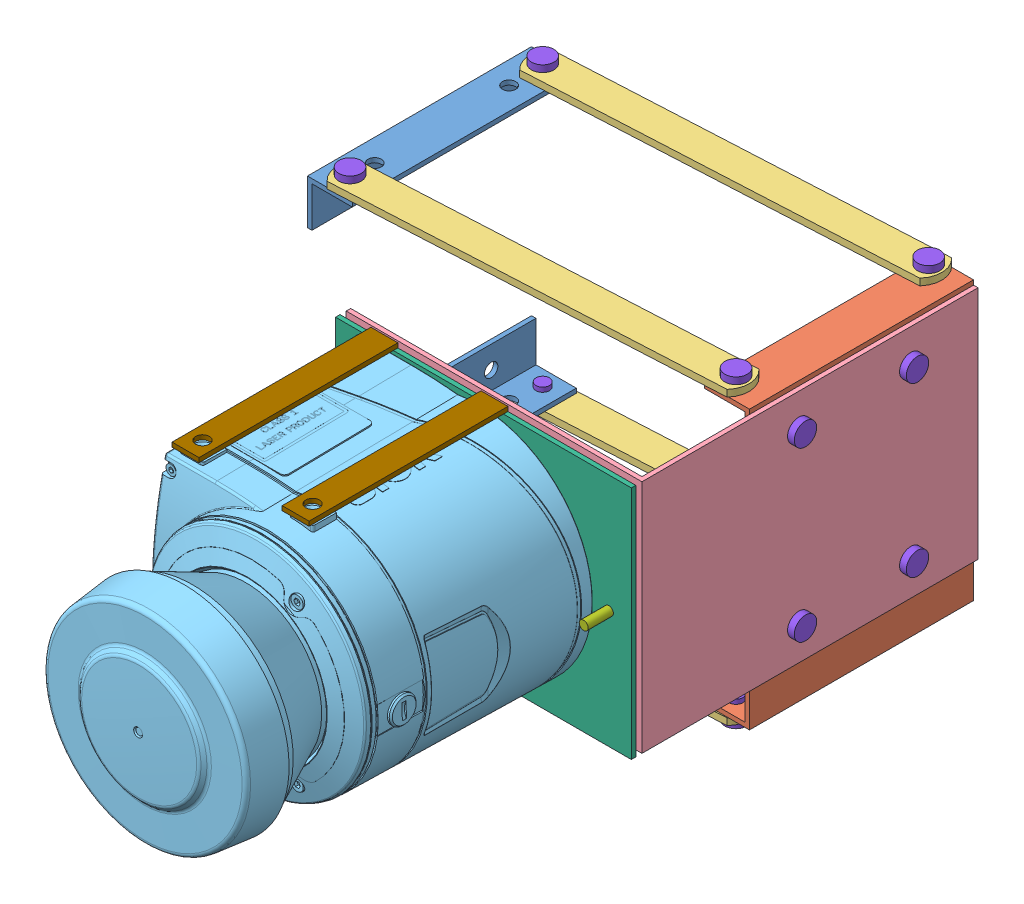
SolidWorks assembly LiDAR Stabilizer, configuration Default. Lengths in mm.
Overall size (193.78 136 307.54).
28 component instances, 9 part files, 52 mates.
Components (placement in the parent):
- l plate-1: l plate [Default] at (18.2462 47.9198 27.6547) size (20 20 100)
- l plate-3: l plate [Default] at (38.2462 -56.0802 27.6547) x (0 1 0) z (0 0 1) size (20 20 100)
- front plate-2: front plate [Default] at (187.0253 67.9198 19.1461) x (0 -1 0) z (0 0 1) size (124 20 100)
- rod-5: rod [Default] at (26.8611 67.9198 27.3205) x (0.998653 0 -0.051882) z (0 1 0) size (176.21 15 3)
- rod-6: rod [Default] at (27.6393 -56.0802 128.3003) x (0.998653 0 -0.051882) z (0 -1 0) size (176.21 15 3)
- rod-7: rod [Default] at (26.8611 67.9198 113.3205) x (0.998653 0 -0.051882) z (0 1 0) size (176.21 15 3)
- rod-8: rod [Default] at (27.6393 -56.0802 42.3003) x (0.998653 0 -0.051882) z (0 -1 0) size (176.21 15 3)
- frontest plate-1: frontest plate [Default] at (207.0253 -39.1421 19.1461) x (0 1 0) z (1 0 0) size (105 150 132)
- LMS111-10100_Dummy-1: LMS111-10100_Dummy [Default] at (80.4216 72.4975 267.6799) x (0.00017 -1 0) z (0 0 1) size (102.32 105.69 161.79)
- lidar base plate-1: lidar base plate [Default] at (2.9052 0 171.893) size (132 105 2)
- angle changing bolt-1: angle changing bolt [Default] at (82.0253 13.3579 164.1461) x (0.352246 -0.935908 0) z (0 0 1) size (10 10 21)
- angle changing bolt-2: angle changing bolt [Default] at (199.0253 13.3579 164.1461) size (10 10 21)
- bolttt-1: bolttt [Default] at (212.0253 50.8579 49.1461) x (0 0 1) z (-1 0 0) size (10 10 10)
- bolttt-2: bolttt [Default] at (212.0253 50.8579 99.1461) x (0 0 1) z (-1 0 0) size (10 10 10)
- bolttt-3: bolttt [Default] at (212.0253 -24.1421 99.1461) x (0 0 1) z (-1 0 0) size (10 10 10)
- bolttt-4: bolttt [Default] at (212.0253 -24.1421 49.1461) x (0 0 1) z (-1 0 0) size (10 10 10)
- bolttt-5: bolttt [Default] at (194.0253 -62.0802 26.1461) x (1 0 0) z (0 1 0) size (10 10 10)
- bolttt-6: bolttt [Default] at (194.0253 -62.0802 112.1461) x (1 0 0) z (0 1 0) size (10 10 10)
- bolttt-7: bolttt [Default] at (30.2462 -62.0802 120.6547) x (1 0 0) z (0 1 0) size (10 10 10)
- bolttt-8: bolttt [Default] at (30.2462 -62.0802 34.6547) x (1 0 0) z (0 1 0) size (10 10 10)
- bolttt-9: bolttt [Default] at (30.2462 73.9198 120.6547) x (1 0 0) z (0 -1 0) size (10 10 10)
- bolttt-10: bolttt [Default] at (30.2462 73.9198 34.6547) x (1 0 0) z (0 -1 0) size (10 10 10)
- bolttt-11: bolttt [Default] at (194.0253 73.9198 26.1461) x (1 0 0) z (0 -1 0) size (10 10 10)
- bolttt-12: bolttt [Default] at (194.0253 73.9198 112.1461) x (1 0 0) z (0 -1 0) size (10 10 10)
- holding lidar-1: holding lidar [Default] at (194.2396 -41.1421 -13.1858) x (1 0 0) z (0 1 0) size (12 88.76 2)
- holding lidar-2: holding lidar [Default] at (242.8499 -41.1421 -13.1858) x (1 0 0) z (0 1 0) size (12 88.76 2)
- holding lidar-3: holding lidar [Default] at (243.0837 65.8579 -13.1858) x (1 0 0) z (0 1 0) size (12 88.76 2)
- holding lidar-4: holding lidar [Default] at (193.9438 65.8579 -13.1858) x (1 0 0) z (0 1 0) size (12 88.76 2)
Mates (geometry in assembly coordinates):
- Coincident8: coincident: plane of assembly; plane of assembly; plane of l plate-1 through (18.2462 47.9198 127.6547) normal (-1 0 0); plane of l plate-3 through (18.2462 -56.0802 127.6547) normal (-1 0 0)
- Coincident9: coincident: plane of assembly; plane of assembly; plane of l plate-1 through (18.2462 47.9198 27.6547) normal (0 0 -1); plane of l plate-3 through (38.2462 -56.0802 27.6547) normal (0 0 -1)
- Coincident10: coincident: plane of assembly; plane of assembly; plane of front plate-2 through (187.0253 67.9198 119.1461) normal (0 1 0); plane of rod-5 through (34.7401 67.9198 34.4213) normal (0 -1 0)
- Coincident11: coincident: circle of assembly; circle of assembly; circle of front plate-2; circle of rod-5
- Coincident12: coincident: circle of assembly; circle of assembly; circle of l plate-1; circle of rod-5
- Coincident13: coincident: circle of assembly; circle of assembly; circle of l plate-1; circle of rod-7
- Coincident14: coincident: circle of front plate-2; circle of rod-7
- Coincident15: coincident: circle of assembly; circle of assembly; circle of front plate-2; circle of rod-8
- Coincident16: coincident: circle of l plate-3; circle of rod-8
- Coincident17: coincident: circle of assembly; circle of assembly; circle of l plate-3; circle of rod-6
- Coincident19: coincident: circle of front plate-2; circle of rod-6
- Parallel1: parallel: plane of assembly; plane of assembly; plane of front plate-2 through (187.0253 67.9198 19.1461) normal (0 0 -1); plane of frontest plate-1 through (209.0253 -39.1421 19.1461) normal (0 0 -1)
- Coincident21: coincident: plane of assembly; plane of assembly; plane of front plate-2 through (207.0253 67.9198 119.1461) normal (1 0 0); plane of frontest plate-1 through (207.0253 -39.1421 19.1461) normal (-1 0 0)
- Coincident22: coincident: line of front plate-2 through (207.0253 -56.0802 19.1461) axis (0 1 0); line of frontest plate-1 through (207.0253 -39.1421 19.1461) axis (0 1 0)
- Lock1: lock: unknown of ?; unknown of ?
- Parallel2: parallel: plane of frontest plate-1 through (209.0253 65.8579 169.1461) normal (0 0 1); plane of lidar base plate-1 through (2.9052 0 171.893) normal (0 0 -1)
- Parallel3: parallel: line of lidar base plate-1 through (209.0253 65.8579 171.893) axis (-1 0 0)
- Parallel4: parallel: line of lidar base plate-1 through (77.0253 65.8579 171.893) axis (0 -1 0)
- Parallel5: parallel: line of lidar base plate-1 through (209.0253 -39.1421 171.893) axis (0 1 0)
- Coincident28: coincident: plane of assembly; plane of assembly; plane of frontest plate-1 through (77.0253 -39.1421 19.1461) normal (-1 0 0); plane of lidar base plate-1 through (77.0253 65.8579 173.893) normal (-1 0 0)
- Coincident30: coincident: plane of assembly; plane of assembly; plane of LMS111-10100_Dummy-1 through (90.3781 13.2901 173.893) normal (0 0 -1); plane of lidar base plate-1 through (2.9052 0 173.893) normal (0 0 1); plane of assembly; plane of assembly; plane of LMS111-10100_Dummy-1; plane of lidar base plate-1
- Parallel7: parallel: plane of LMS111-10100_Dummy-1 through (90.5705 18.5363 191.0305) normal (-1 0 0); plane of lidar base plate-1 through (77.0253 65.8579 173.893) normal (-1 0 0)
- Concentric1: concentric: circle of assembly; circle of assembly; circle of frontest plate-1; circle of lidar base plate-1
- Coincident32: coincident: plane of assembly; plane of assembly; plane of frontest plate-1 through (77.0253 -39.1421 19.1461) normal (-1 0 0); plane of lidar base plate-1 through (77.0253 65.8579 173.893) normal (-1 0 0)
- Lock2: lock: unknown of frontest plate-1; unknown of lidar base plate-1
- Coincident33: coincident: circle of assembly; circle of assembly; circle of frontest plate-1; circle of angle changing bolt-1
- Coincident34: coincident: circle of assembly; circle of assembly; circle of frontest plate-1; circle of angle changing bolt-2
- Coincident35: coincident: circle of assembly; circle of assembly; circle of frontest plate-1; circle of bolttt-1
- Coincident37: coincident: circle of assembly; circle of assembly; circle of frontest plate-1; circle of bolttt-3
- Coincident38: coincident: circle of assembly; circle of assembly; circle of frontest plate-1; circle of bolttt-4
- Coincident39: coincident: circle of assembly; circle of assembly; circle of frontest plate-1; circle of bolttt-2
- Coincident40: coincident: circle of rod-6; circle of bolttt-6
- Coincident41: coincident: circle of rod-8; circle of bolttt-5
- Coincident42: coincident: circle of rod-8; circle of bolttt-8
- Coincident43: coincident: circle of rod-6; circle of bolttt-7
- Coincident44: coincident: circle of rod-7; circle of bolttt-12
- Coincident45: coincident: circle of assembly; circle of assembly; circle of rod-5; circle of bolttt-11
- Coincident46: coincident: circle of assembly; circle of assembly; circle of rod-5; circle of bolttt-10
- Coincident47: coincident: circle of rod-7; circle of bolttt-9
- Lock3: lock: unknown of LMS111-10100_Dummy-1; unknown of lidar base plate-1
- Coincident49: coincident: plane of assembly; plane of assembly; plane of lidar base plate-1 through (77.0253 -39.1421 173.893) normal (0 -1 0); plane of holding lidar-1 through (194.2396 -39.1421 -13.1858) normal (0 1 0)
- Coincident50: coincident: line of holding lidar-1 through (91.1198 -39.1421 260.657) axis (0 0 -1)
- Coincident51: coincident: line of holding lidar-1 through (91.1198 -39.1421 171.893) axis (1 0 0)
- Coincident52: coincident: plane of assembly; plane of assembly; plane of lidar base plate-1 through (77.0253 -39.1421 173.893) normal (0 -1 0); plane of holding lidar-2 through (242.8499 -39.1421 -13.1858) normal (0 1 0)
- Coincident53: coincident: line of lidar base plate-1 through (77.0253 -39.1421 171.893) axis (1 0 0); line of holding lidar-2 through (139.7301 -39.1421 171.893) axis (1 0 0)
- Lock4: lock: unknown of LMS111-10100_Dummy-1; unknown of holding lidar-2
- Coincident54: coincident: plane of assembly; plane of assembly; plane of lidar base plate-1 through (209.0253 65.8579 173.893) normal (0 1 0); plane of holding lidar-3 through (243.0837 65.8579 -13.1858) normal (0 -1 0)
- Coincident55: coincident: line of lidar base plate-1 through (209.0253 65.8579 171.893) axis (-1 0 0); line of holding lidar-3 through (139.9639 65.8579 171.893) axis (1 0 0)
- Lock5: lock: unknown of lidar base plate-1; unknown of holding lidar-3
- Coincident57: coincident: line of lidar base plate-1 through (209.0253 65.8579 171.893) axis (-1 0 0); line of holding lidar-4 through (90.824 65.8579 171.893) axis (1 0 0)
- Coincident58: coincident: plane of lidar base plate-1 through (209.0253 65.8579 173.893) normal (0 1 0); plane of holding lidar-4 through (193.9438 65.8579 -13.1858) normal (0 -1 0)
- Lock6: lock: unknown of holding lidar-4
